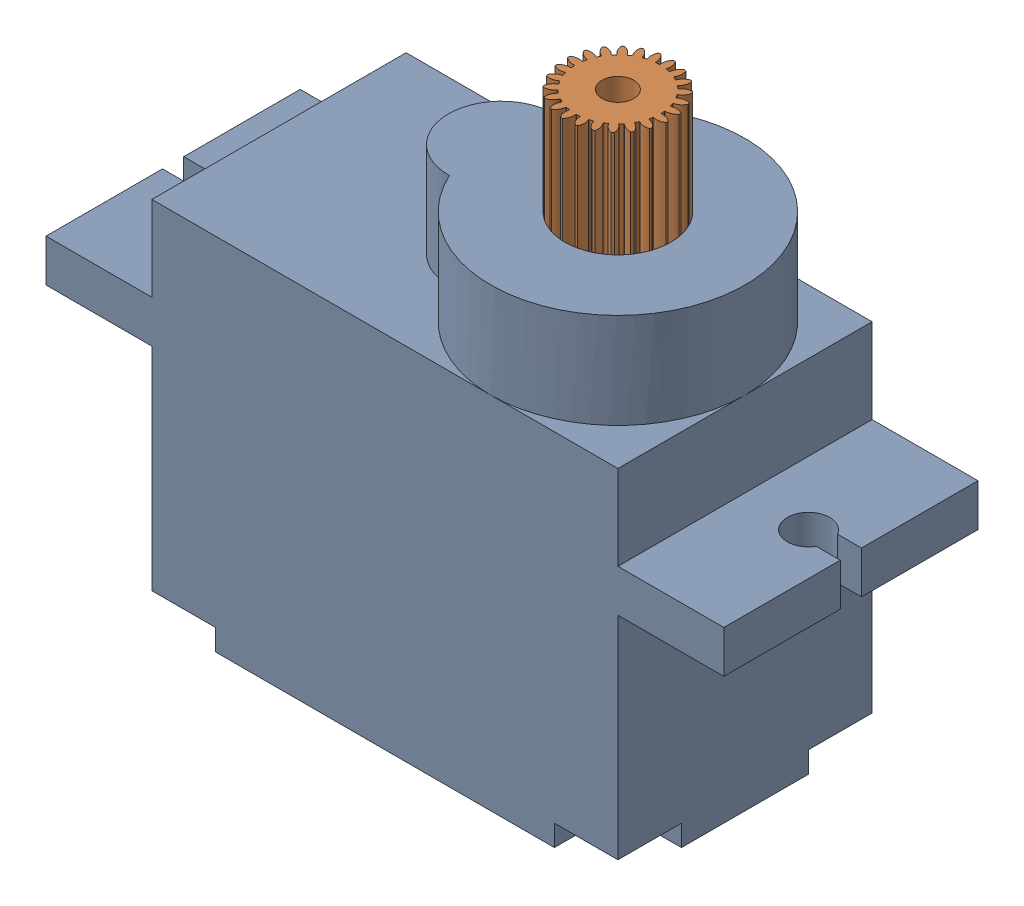
SolidWorks assembly SG-90, configuration Predeterminado. Lengths in mm.
Overall size (32 26.5 12).
2 component instances, 2 part files, 2 mates.
Components (placement in the parent):
- Pieza1-1: Pieza1 [Predeterminado] at (-4.6869 32 1.6404) size (32 21.5 12)
- PZ2-1: PZ2 [Predeterminado] at (0.3131 58.5 1.6404) x (0.702574 0 -0.71161) z (0.71161 0 0.702574) size (4.99 10 4.99)
Mates (geometry in assembly coordinates):
- Concéntrica1: concentric: circle of Pieza1-1; circle of PZ2-1
- Coincidente1: coincident anti-aligned: plane of Pieza1-1 through (0.3131 48.5 1.6404) normal (0 1 0); plane of PZ2-1 through (0.3131 48.5 1.6404) normal (0 -1 0)
